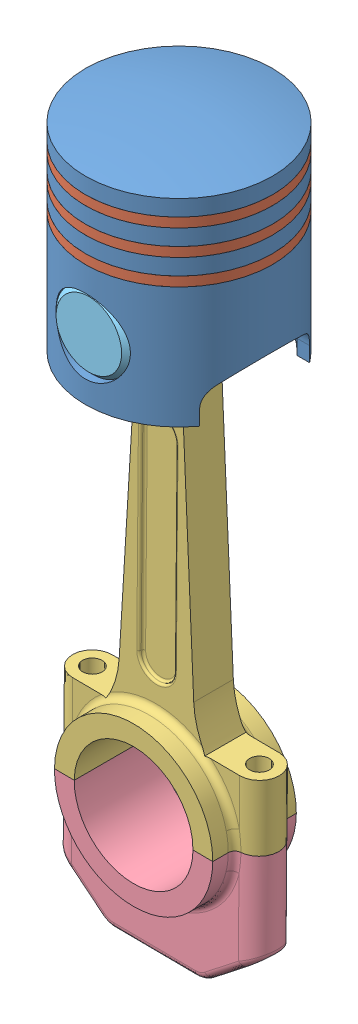
SolidWorks assembly Piston  and connecting rod, configuration Default. Lengths in mm.
Overall size (119.69 329.58 119.69).
7 component instances, 5 part files, 13 mates.
Components (placement in the parent):
- 1. Piston-1: 1. Piston [Default] at (30.8042 3.5612 74.369) size (85 95 85)
- 2. Piston ring-1: 2. Piston ring [Default] at (30.8042 81.9612 74.369) x (0.281683 0 0.959508) z (-0.959508 0 0.281683) size (85 4.3 85)
- 4. Connecting rod-1: 4. Connecting rod [Default] at (30.8042 30.5612 74.369) x (0.999967 -0.008182 0) z (0 0 1) size (94 223.7 38)
- 5. Connecting rod cap-1: 5. Connecting rod cap [Default] at (29.1579 -170.6321 74.369) x (0.999967 -0.008182 0) z (0 0 -1) size (94 60 38)
- 6. Piston pin-1: 6. Piston pin [Default] at (30.8042 30.5612 74.369) size (33.8 33.8 82)
- 2. Piston ring-2: 2. Piston ring [Default] at (30.8042 70.3612 74.369) x (0.457459 0 0.88923) z (-0.88923 0 0.457459) size (85 4.3 85)
- 2. Piston ring-4: 2. Piston ring [Default] at (30.8042 58.7612 74.369) x (0.638398 0 0.769707) z (-0.769707 0 0.638398) size (85 4.3 85)
Mates (geometry in assembly coordinates):
- Concentric1: concentric anti-aligned: cylinder of 1. Piston-1 through (30.8042 81.9612 74.369) axis (0 1 0) radius 39.5; cylinder of 2. Piston ring-1 through (30.8042 86.2612 74.369) axis (0 -1 0) radius 39.5
- Coincident1: coincident anti-aligned: plane of 1. Piston-1 through (30.8042 81.9612 74.369) normal (0 1 0); plane of 2. Piston ring-1 through (30.8042 81.9612 74.369) normal (0 -1 0)
- Concentric2: concentric anti-aligned: cylinder of 1. Piston-1 through (30.8042 70.3612 74.369) axis (0 1 0) radius 39.5; cylinder of 2. Piston ring-2 through (30.8042 74.6612 74.369) axis (0 -1 0) radius 39.5
- Coincident2: coincident anti-aligned: plane of 1. Piston-1 through (30.8042 70.3612 74.369) normal (0 1 0); plane of 2. Piston ring-2 through (30.8042 70.3612 74.369) normal (0 -1 0)
- Concentric3: concentric anti-aligned: cylinder of 1. Piston-1 through (30.8042 58.7612 74.369) axis (0 1 0) radius 39.5; cylinder of 2. Piston ring-4 through (30.8042 63.0612 74.369) axis (0 -1 0) radius 39.5
- Coincident3: coincident anti-aligned: plane of 1. Piston-1 through (30.8042 58.7612 74.369) normal (0 1 0); plane of 2. Piston ring-4 through (30.8042 58.7612 74.369) normal (0 -1 0)
- Coincident4: coincident aligned: plane of 1. Piston-1 through (30.8042 3.5612 74.369) normal (0 0 1); plane of 6. Piston pin-1 through (30.8042 30.5612 74.369) normal (0 0 1)
- Concentric4: concentric anti-aligned: cylinder of 1. Piston-1 through (30.8042 30.5612 31.869) axis (0 0 1) radius 16.9; cylinder of 6. Piston pin-1 through (30.8042 30.5612 115.369) axis (0 0 -1) radius 16.9
- Coincident5: coincident aligned: plane of 1. Piston-1 through (30.8042 3.5612 74.369) normal (0 0 1); plane of 4. Connecting rod-1 through (30.8042 30.5612 74.369) normal (0 0 1)
- Concentric5: concentric aligned: cylinder of 4. Connecting rod-1 through (30.8042 30.5612 93.369) axis (0 0 -1) radius 16.9; cylinder of 6. Piston pin-1 through (30.8042 30.5612 115.369) axis (0 0 -1) radius 16.9
- Concentric6: concentric aligned: cylinder of 4. Connecting rod-1 through (67.1566 -170.943 74.369) axis (0.008182 0.999967 0) radius 4.5; cylinder of 5. Connecting rod cap-1 through (66.6657 -230.941 74.369) axis (0.008182 0.999967 0) radius 4.5
- Concentric7: concentric aligned: cylinder of 4. Connecting rod-1 through (-8.8408 -170.3211 74.369) axis (0.008182 0.999967 0) radius 4.5; cylinder of 5. Connecting rod cap-1 through (-9.3318 -230.3191 74.369) axis (0.008182 0.999967 0) radius 4.5
- Coincident6: coincident anti-aligned: plane of 4. Connecting rod-1 through (29.1579 -170.6321 93.369) normal (-0.008182 -0.999967 0); plane of 5. Connecting rod cap-1 through (-6.8409 -170.3375 55.369) normal (0.008182 0.999967 0)
